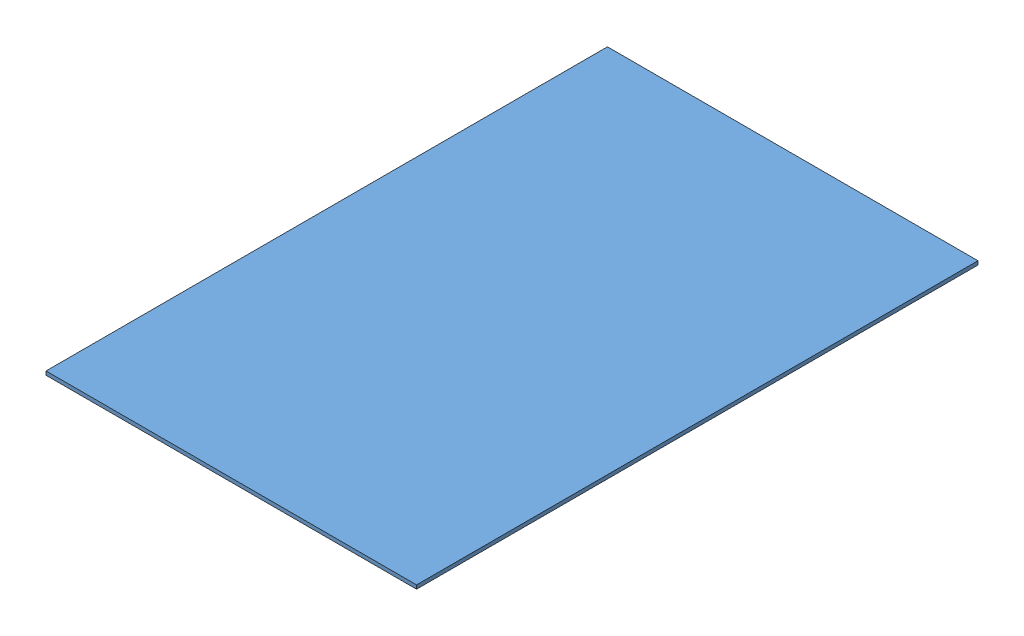
SolidWorks assembly milling-2mm, configuration Default. Lengths in mm.
Overall size (198 2 300).
4 component instances, 3 part files, 9 mates.
Components (placement in the parent):
- stock-carbon-2mm-1: stock-carbon-2mm [Default] at origin size (198 2 300)
- camera-mount-1: camera-mount [Left] at (23 1 127.5) x (0 1 0) z (0 0 -1) size (2 37 43.43)
- camera-mount-2: camera-mount [Right] at (96 1 127.5) x (0 -1 0) z (0 0 -1) size (2 37 43.43)
- frame-bottom-1: frame-bottom [Bottom] at (82 2 51.6433) x (1 0 0) z (0 0 -1) size (32 2 91.65)
Mates (geometry in assembly coordinates):
- Coincident1: coincident aligned: plane of stock-carbon-2mm-1 through (0 0 0) normal (0 -1 0); plane of camera-mount-2 through (96 0 127.5) normal (0 -1 0)
- Coincident2: coincident aligned: plane of stock-carbon-2mm-1 through (0 0 0) normal (0 -1 0); plane of camera-mount-1 through (23 0 127.5) normal (0 -1 0)
- Distance1: distance = 1 mm aligned: plane of camera-mount-2 through (98 0 127.5) normal (1 0 0); plane of stock-carbon-2mm-1 through (99 2 -150) normal (1 0 0)
- Distance2: distance = 1 mm aligned: plane of camera-mount-2 through (96 0 149) normal (0 0 1); plane of stock-carbon-2mm-1 through (99 2 150) normal (0 0 1)
- Distance3: distance = 1 mm aligned: plane of camera-mount-1 through (23 2 149) normal (0 0 1); plane of stock-carbon-2mm-1 through (99 2 150) normal (0 0 1)
- Distance4: distance = 3 mm anti-aligned: plane of camera-mount-1 through (58 2 127.5) normal (1 0 0); plane of camera-mount-2 through (61 0 127.5) normal (-1 0 0)
- Coincident7: coincident aligned: plane of stock-carbon-2mm-1 through (0 0 0) normal (0 -1 0); plane of frame-bottom-1 through (82 0 51.6433) normal (0 -1 0)
- Distance5: distance = 1 mm aligned: plane of frame-bottom-1 through (98 0 51.6433) normal (1 0 0); plane of stock-carbon-2mm-1 through (99 2 -150) normal (1 0 0)
- Distance7: distance = 3 mm anti-aligned: plane of frame-bottom-1 through (82 0 102.5683) normal (0 0 1); cylinder of camera-mount-2 through (81 0 127.5) axis (0 1 0) radius 21.9317
